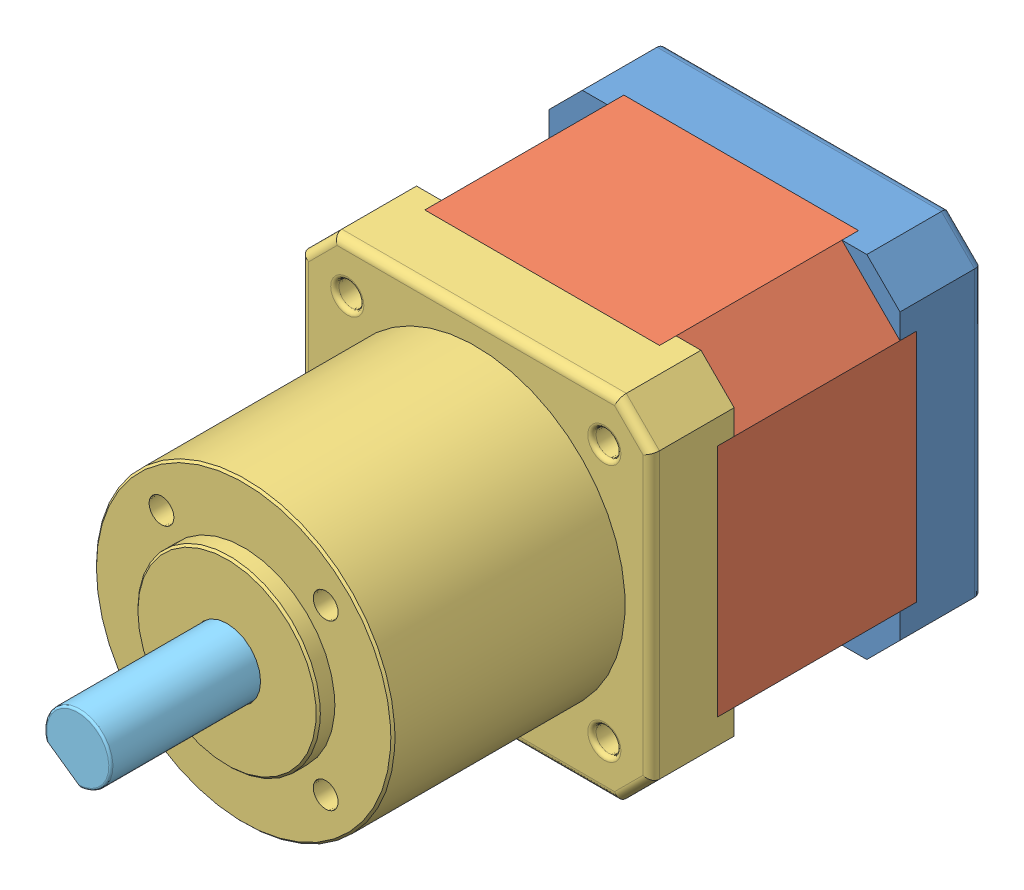
SolidWorks assembly NEMA_17_5.18_Planetary, configuration Default. Lengths in mm.
Overall size (42.3 42.3 88.03).
10 component instances, 6 part files, 0 mates.
Components (placement in the parent):
- Base_Planetary-1: Base_Planetary [Default] at (-10.3955 4.6172 0) size (42.3 42.3 10)
- Body_Planetary-1: Body_Planetary [Default] at (-10.3955 4.6172 8) size (42.3 42.3 24)
- FaceCap_Planetary-1: FaceCap_Planetary [Default] at (-10.3955 4.6172 40) x (-1 0 0) z (0 0 -1) size (42.3 42.3 40)
- pan cross head_am(B18.6.7M - M3 x 0.5 x 16 Type I Cross Recessed PHMS --16N)-1: pan cross head_am(B18.6.7M - M3 x 0.5 x 16 Type I Cross Recessed PHMS --16N) [Default] at (5.1045 20.1172 0.6) x (0 0 1) z (-0.896 0.444054 0) size (18.37 5.6 5.6)
- pan cross head_am(B18.6.7M - M3 x 0.5 x 16 Type I Cross Recessed PHMS --16N)-2: pan cross head_am(B18.6.7M - M3 x 0.5 x 16 Type I Cross Recessed PHMS --16N) [Default] at (-25.8955 -10.8828 0.6) x (0 0 1) z (-0.91385 -0.406051 0) size (18.37 5.6 5.6)
- pan cross head_am(B18.6.7M - M3 x 0.5 x 16 Type I Cross Recessed PHMS --16N)-3: pan cross head_am(B18.6.7M - M3 x 0.5 x 16 Type I Cross Recessed PHMS --16N) [Default] at (5.1045 -10.8828 0.6) x (0 0 1) z (-0.883632 0.468182 0) size (18.37 5.6 5.6)
- pan cross head_am(B18.6.7M - M3 x 0.5 x 16 Type I Cross Recessed PHMS --16N)-4: pan cross head_am(B18.6.7M - M3 x 0.5 x 16 Type I Cross Recessed PHMS --16N) [Default] at (-25.8955 20.1172 0.6) x (0 0 1) z (-0.859432 0.51125 0) size (18.37 5.6 5.6)
- Shaft_Planetary-1: Shaft_Planetary [Default] at (-10.3955 4.6172 0) x (0.574856 0.818255 0) z (0 0 1) size (8 8 88.03)
- instrument ball bearing_68_am(PreviewCfg)-1: instrument ball bearing_68_am(PreviewCfg) [Default] at (-10.3955 4.6172 36.4125) x (0 0 1) z (0.959468 0.281819 0) size (3.17 12.7 12.7)
- instrument ball bearing_68_am(PreviewCfg)-2: instrument ball bearing_68_am(PreviewCfg) [Default] at (-10.3955 4.6172 3.4125) x (0 0 1) z (-0.739703 -0.672934 0) size (3.17 12.7 12.7)
